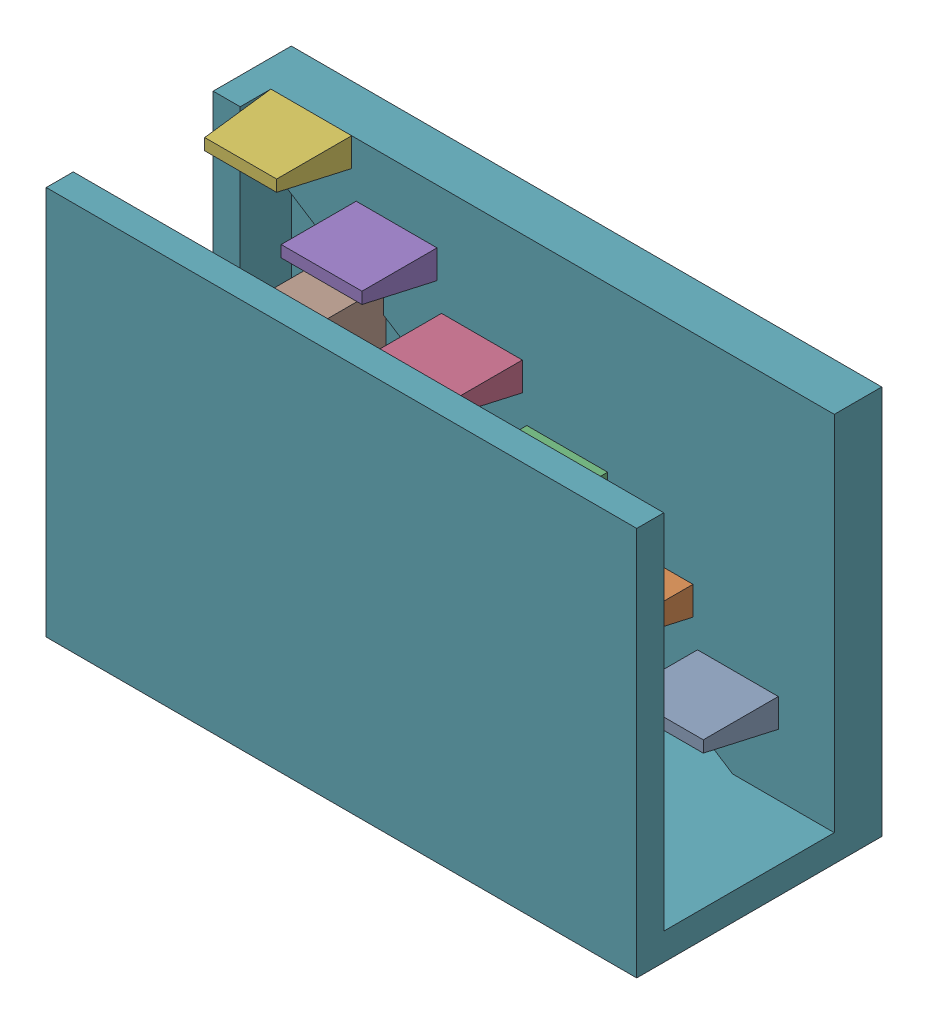
SolidWorks assembly Ensamblaje3, configuration Predeterminado. Lengths in mm.
Overall size (3324.8 2192.4 1379.8).
4 component instances, 4 part files, 6 mates.
Components (placement in the parent):
- EspacioEscalera-1: EspacioEscalera [Predeterminado] at (-152.0858 -897.9243 0) size (3324.8 2192.4 1379.8)
- MuebleLimpieza-1: MuebleLimpieza [Predeterminado] at (-1177.6818 -802.9243 -243.7921) size (300 1300 385)
- TanqueDePresion-1: TanqueDePresion [Predeterminado] at (-624.4745 122.0757 -157.1117) x (1 0 0) z (0 -1 0) size (610 450 1020)
- BombaDeAgua-2: BombaDeAgua [Predeterminado] at (-136.86 -780.4243 -236.5578) size (249 235 235)
Mates (geometry in assembly coordinates):
- Coincidente2: coincident anti-aligned: plane of EspacioEscalera-1 through (-152.0858 -897.9243 0) normal (0 1 0); plane of TanqueDePresion-1 through (-624.4745 -897.9243 -157.1117) normal (0 -1 0)
- Coincidente3: coincident anti-aligned: line of EspacioEscalera-1 through (1510.3142 -802.9243 537.5) axis (-1 0 0); plane of MuebleLimpieza-1 through (-1177.6818 -802.9243 -243.7921) normal (0 -1 0)
- Paralelo1: parallel anti-aligned: plane of EspacioEscalera-1 through (-152.0858 -897.9243 0) normal (0 1 0); plane of MuebleLimpieza-1 through (-1177.6818 -802.9243 -243.7921) normal (0 -1 0)
- Paralelo2: parallel anti-aligned: plane of EspacioEscalera-1 through (-152.0858 -897.9243 0) normal (0 1 0); plane of BombaDeAgua-2 through (-36.86 -897.9243 -1.5578) normal (0 -1 0)
- Coincidente8: coincident anti-aligned: plane of EspacioEscalera-1 through (-152.0858 -897.9243 0) normal (0 1 0); plane of BombaDeAgua-2 through (-36.86 -897.9243 -1.5578) normal (0 -1 0)
- Paralelo4: parallel anti-aligned: plane of EspacioEscalera-1 through (-152.0858 -897.9243 0) normal (0 1 0); plane of MuebleLimpieza-1 through (-1177.6818 -802.9243 -243.7921) normal (0 -1 0)
